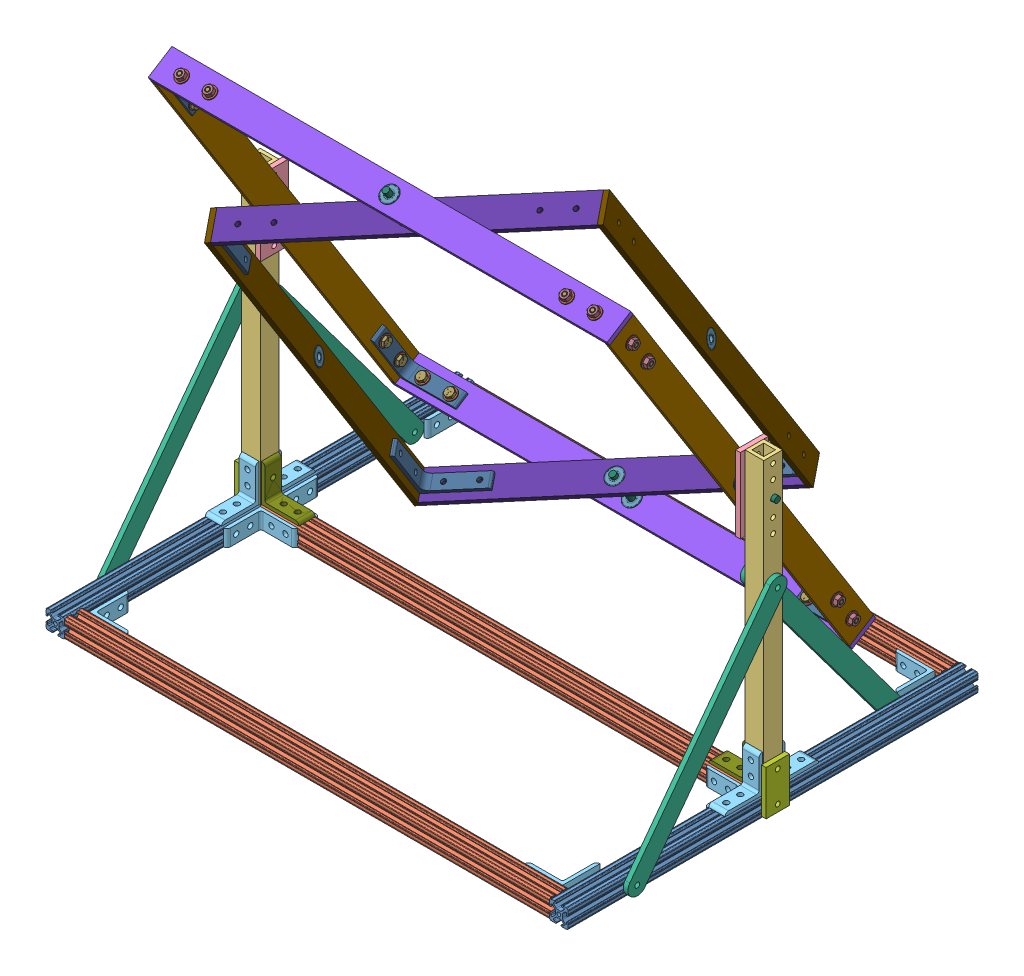
SolidWorks assembly Tines_Assy, configuration Default. Lengths in mm.
Overall size (720.72 664.68 555.62).
126 component instances, 18 part files, 37 mates.
Components (placement in the parent):
- TinesBase_Rails-1: TinesBase_Rails [47065T568] at (481.4535 301.031 444.4013) size (25.4 25.4 555.62)
- TinesBase_Stretcher-5: TinesBase_Stretcher [47065T568] at (140.141 301.031 179.2888) x (0 0 -1) z (1 0 0) size (25.4 25.4 657.22)
- TinesBase_Stretcher-6: TinesBase_Stretcher [47065T568] at (140.141 301.031 444.4013) x (0 0 -1) z (1 0 0) size (25.4 25.4 657.22)
- TinesBase_Stretcher-7: TinesBase_Stretcher [47065T568] at (140.141 301.031 709.5138) x (0 0 -1) z (1 0 0) size (25.4 25.4 657.22)
- TinesBase_Rails-3: TinesBase_Rails [47065T568] at (-201.1715 301.031 444.4013) size (25.4 25.4 555.62)
- Tines_Post-2: Tines_Post [47065T568] at (481.4535 510.581 444.4013) x (1 0 0) z (0 -1 0) size (25.4 25.4 393.7)
- Tines_Post-3: Tines_Post [47065T568] at (-201.1715 510.581 444.4013) x (1 0 0) z (0 -1 0) size (25.4 25.4 393.7)
- BearingSpacer^Tines_Assy-1: BearingSpacer^Tines_Assy [Default] at (462.4035 656.631 444.4013) x (0 -1 0) z (0 0 1) size (101.6 6.35 38.1) (virtual)
- BearingSpacer^Tines_Assy-2: BearingSpacer^Tines_Assy [Default] at (-188.4715 656.631 444.4013) x (0 -1 0) z (0 0 1) size (101.6 6.35 38.1) (virtual)
- 47065T239_Silver Corner Bracket-1: 47065T239_Silver Corner Bracket [47065T239] at (-180.817 301.031 696.8138) x (1 0 0) z (0 1 0) size (50.8 50.8 22.23)
- 47065T239_Silver Corner Bracket-2: 47065T239_Silver Corner Bracket [47065T239] at (-188.4715 301.031 456.3075) x (1 0 0) z (0 -1 0) size (50.8 50.8 22.23)
- 47065T239_Silver Corner Bracket-5: 47065T239_Silver Corner Bracket [47065T239] at (461.099 301.031 696.8138) x (-1 0 0) z (0 -1 0) size (50.8 50.8 22.23)
- 47065T239_Silver Corner Bracket-6: 47065T239_Silver Corner Bracket [47065T239] at (468.7535 301.031 456.3075) x (-1 0 0) z (0 1 0) size (50.8 50.8 22.23)
- 47065T239_Silver Corner Bracket-9: 47065T239_Silver Corner Bracket [47065T239] at (-180.817 301.031 191.9888) x (1 0 0) z (0 -1 0) size (50.8 50.8 22.23)
- 47065T239_Silver Corner Bracket-10: 47065T239_Silver Corner Bracket [47065T239] at (-188.4715 301.031 432.495) x (1 0 0) z (0 1 0) size (50.8 50.8 22.23)
- 47065T239_Silver Corner Bracket-11: 47065T239_Silver Corner Bracket [47065T239] at (461.099 301.031 191.9888) x (-1 0 0) z (0 1 0) size (50.8 50.8 22.23)
- 47065T239_Silver Corner Bracket-12: 47065T239_Silver Corner Bracket [47065T239] at (468.7535 301.031 432.495) x (-1 0 0) z (0 -1 0) size (50.8 50.8 22.23)
- 47065T239_Silver Corner Bracket-13: 47065T239_Silver Corner Bracket [47065T239] at (-201.1715 313.731 457.1013) x (0 1 0) z (1 0 0) size (50.8 50.8 22.23)
- 47065T239_Silver Corner Bracket-14: 47065T239_Silver Corner Bracket [47065T239] at (481.4535 313.731 457.1013) x (0 1 0) z (1 0 0) size (50.8 50.8 22.23)
- 47065T239_Silver Corner Bracket-15: 47065T239_Silver Corner Bracket [47065T239] at (-201.1715 313.731 431.7013) x (0 1 0) z (-1 0 0) size (50.8 50.8 22.23)
- 47065T239_Silver Corner Bracket-16: 47065T239_Silver Corner Bracket [47065T239] at (481.4535 313.731 431.7013) x (0 1 0) z (-1 0 0) size (50.8 50.8 22.23)
- Big Bar^Tines_Assy-1: Big Bar^Tines_Assy [Default] at (462.4035 428.031 349.1513) x (0 -0.8 -0.6) z (0 -0.6 0.8) size (342.9 6.35 25.4) (virtual)
- Big Bar^Tines_Assy-2: Big Bar^Tines_Assy [Default] at (494.1535 428.031 539.6513) x (0 -0.8 0.6) z (0 0.6 0.8) size (342.9 6.35 25.4) (virtual)
- Big Bar^Tines_Assy-3: Big Bar^Tines_Assy [Default] at (-213.8715 428.031 539.6513) x (0 -0.8 0.6) z (0 -0.6 -0.8) size (342.9 6.35 25.4) (virtual)
- Big Bar^Tines_Assy-4: Big Bar^Tines_Assy [Default] at (-182.1215 428.031 349.1513) x (0 -0.8 -0.6) z (0 0.6 -0.8) size (342.9 6.35 25.4) (virtual)
- TinesPost Facebracket^Tines_Assy-1: TinesPost Facebracket^Tines_Assy [Default] at (494.1535 321.6685 444.4013) x (0 -1 0) z (0 0 1) size (60.32 6.35 31.75) (virtual)
- TinesPost Facebracket^Tines_Assy-2: TinesPost Facebracket^Tines_Assy [Default] at (-213.8715 321.6685 444.4013) x (0 -1 0) z (0 0 -1) size (60.32 6.35 31.75) (virtual)
- OutR_22mm-2: OutR_22mm [Default] at (139.924 656.2272 445.0411) x (0.999995 0.001674 -0.002652) z (-0.003135 0.533741 -0.845642) size (717.82 639.44 40.05)
  - OutR_L_22mm-1: OutR_L_22mm [Default] at (0.2194 -311.15 0.7559) x (0.999995 0 -0.003135) z (0.003135 0 0.999995) size (622.3 6.35 38.1)
  - OutR_L_22mm-2: OutR_L_22mm [Default] at (0.2194 311.15 0.7559) x (-0.999995 0 0.003135) z (0.003135 0 0.999995) size (622.3 6.35 38.1)
  - OutR_S_22mm-1: OutR_S_22mm [Default] at (-304.5791 0 1.7116) x (0 1 0) z (0.003135 0 0.999995) size (609.6 6.35 38.1)
  - OutR_S_22mm-2: OutR_S_22mm [Default] at (305.0179 0 -0.1998) x (0 -1 0) z (0.003135 0 0.999995) size (609.6 6.35 38.1)
  - Stand_Bracket_3in-1: Stand_Bracket_3in [8982K254] at (266.9181 266.7 -0.0803) x (0.999995 0 -0.003135) z (-0.003135 0 -0.999995) size (76.2 76.2 19.05)
  - Stand_Bracket_3in-2: Stand_Bracket_3in [8982K254] at (-266.7 266.9181 -0.0803) x (0 0.999995 -0.003135) z (0 -0.003135 -0.999995) size (76.2 76.2 19.05)
  - Stand_Bracket_3in-3: Stand_Bracket_3in [8982K254] at (-266.9181 -266.7 -0.0803) x (-0.999995 0 -0.003135) z (0.003135 0 -0.999995) size (76.2 76.2 19.05)
  - Stand_Bracket_3in-4: Stand_Bracket_3in [8982K254] at (266.7 -266.9181 -0.0803) x (0 -0.999995 -0.003135) z (0 0.003135 -0.999995) size (76.2 76.2 19.05)
  - 90107A029_316 Stainless Steel Washer-1: 90107A029_316 Stainless Steel Washer [90107A029] at (241.5182 298.9453 -0.0007) size (15.88 1.09 15.88)
  - 92965A540_Black-Oxide Grade 5 Steel Hex Head Screws-1: 92965A540_Black-Oxide Grade 5 Steel Hex Head Screws [92965A540] at (241.5182 306.4859 -0.0007) x (0 1 0) z (-0.999784 0 0.020761) size (23.49 12.83 11.11)
  - 95462A029_Medium-Strength Steel Hex Nut-1: 95462A029_Medium-Strength Steel Hex Nut [95462A029] at (241.5182 315.0203 -0.0007) x (0.295019 0 -0.955491) z (0 1 0) size (11.11 12.83 6.51)
  - 90107A029_316 Stainless Steel Washer-2: 90107A029_316 Stainless Steel Washer [90107A029] at (241.5182 311.15 -0.0007) size (15.88 1.09 15.88)
  - 90107A029_316 Stainless Steel Washer-3: 90107A029_316 Stainless Steel Washer [90107A029] at (279.618 311.15 -0.1201) size (15.88 1.09 15.88)
  - 95462A029_Medium-Strength Steel Hex Nut-2: 95462A029_Medium-Strength Steel Hex Nut [95462A029] at (279.618 315.0203 -0.1201) x (0.295019 0 -0.955491) z (0 1 0) size (11.11 12.83 6.51)
  - 92965A540_Black-Oxide Grade 5 Steel Hex Head Screws-2: 92965A540_Black-Oxide Grade 5 Steel Hex Head Screws [92965A540] at (279.618 306.4859 -0.1201) x (0 1 0) z (-0.999784 0 0.020761) size (23.49 12.83 11.11)
  - 90107A029_316 Stainless Steel Washer-4: 90107A029_316 Stainless Steel Washer [90107A029] at (279.618 298.9453 -0.1201) size (15.88 1.09 15.88)
  - 90107A029_316 Stainless Steel Washer-5: 90107A029_316 Stainless Steel Washer [90107A029] at (299.1632 241.3 -0.1814) x (0.00001 0.999995 0.003135) z (-0.003135 0.003135 -0.99999) size (15.88 1.09 15.88)
  - 92965A540_Black-Oxide Grade 5 Steel Hex Head Screws-3: 92965A540_Black-Oxide Grade 5 Steel Hex Head Screws [92965A540] at (306.7038 241.3 -0.2051) x (0.999995 0 -0.003135) z (-0.000055 0.999845 -0.017626) size (23.49 12.83 11.11)
  - 95462A029_Medium-Strength Steel Hex Nut-3: 95462A029_Medium-Strength Steel Hex Nut [95462A029] at (315.2392 241.3 -0.2318) x (-0.002993 0.298014 -0.954557) z (-0.999995 0 0.003135) size (11.11 12.83 6.51)
  - 90107A029_316 Stainless Steel Washer-6: 90107A029_316 Stainless Steel Washer [90107A029] at (311.3679 241.3 -0.2197) x (0.00001 0.999995 0.003135) z (-0.003135 0.003135 -0.99999) size (15.88 1.09 15.88)
  - 90107A029_316 Stainless Steel Washer-7: 90107A029_316 Stainless Steel Washer [90107A029] at (311.3679 279.4 -0.2197) x (0.00001 0.999995 0.003135) z (-0.003135 0.003135 -0.99999) size (15.88 1.09 15.88)
  - 95462A029_Medium-Strength Steel Hex Nut-4: 95462A029_Medium-Strength Steel Hex Nut [95462A029] at (315.2392 279.4 -0.2318) x (-0.002993 0.298014 -0.954557) z (-0.999995 0 0.003135) size (11.11 12.83 6.51)
  - 92965A540_Black-Oxide Grade 5 Steel Hex Head Screws-4: 92965A540_Black-Oxide Grade 5 Steel Hex Head Screws [92965A540] at (306.7038 279.4 -0.2051) x (0.999995 0 -0.003135) z (-0.000055 0.999845 -0.017626) size (23.49 12.83 11.11)
  - 90107A029_316 Stainless Steel Washer-8: 90107A029_316 Stainless Steel Washer [90107A029] at (299.1632 279.4 -0.1814) x (0.00001 0.999995 0.003135) z (-0.003135 0.003135 -0.99999) size (15.88 1.09 15.88)
  - 90107A029_316 Stainless Steel Washer-9: 90107A029_316 Stainless Steel Washer [90107A029] at (-241.3 299.1632 -0.1814) x (-0.999995 0.00001 0.003135) z (-0.003135 -0.003135 -0.99999) size (15.88 1.09 15.88)
  - 90107A029_316 Stainless Steel Washer-10: 90107A029_316 Stainless Steel Washer [90107A029] at (-299.1632 -241.3 -0.1814) x (-0.00001 -0.999995 0.003135) z (0.003135 -0.003135 -0.99999) size (15.88 1.09 15.88)
  - 90107A029_316 Stainless Steel Washer-11: 90107A029_316 Stainless Steel Washer [90107A029] at (241.3 -299.1632 -0.1814) x (0.999995 -0.00001 0.003135) z (0.003135 0.003135 -0.99999) size (15.88 1.09 15.88)
  - 92965A540_Black-Oxide Grade 5 Steel Hex Head Screws-5: 92965A540_Black-Oxide Grade 5 Steel Hex Head Screws [92965A540] at (-241.3 306.7038 -0.2051) x (0 0.999995 -0.003135) z (-0.999845 -0.000055 -0.017626) size (23.49 12.83 11.11)
  - 92965A540_Black-Oxide Grade 5 Steel Hex Head Screws-6: 92965A540_Black-Oxide Grade 5 Steel Hex Head Screws [92965A540] at (-306.7038 -241.3 -0.2051) x (-0.999995 0 -0.003135) z (0.000055 -0.999845 -0.017626) size (23.49 12.83 11.11)
  - 92965A540_Black-Oxide Grade 5 Steel Hex Head Screws-7: 92965A540_Black-Oxide Grade 5 Steel Hex Head Screws [92965A540] at (241.3 -306.7038 -0.2051) x (0 -0.999995 -0.003135) z (0.999845 0.000055 -0.017626) size (23.49 12.83 11.11)
  - 95462A029_Medium-Strength Steel Hex Nut-5: 95462A029_Medium-Strength Steel Hex Nut [95462A029] at (-241.3 315.2392 -0.2318) x (-0.298014 -0.002993 -0.954557) z (0 -0.999995 0.003135) size (11.11 12.83 6.51)
  - 95462A029_Medium-Strength Steel Hex Nut-6: 95462A029_Medium-Strength Steel Hex Nut [95462A029] at (-315.2392 -241.3 -0.2318) x (0.002993 -0.298014 -0.954557) z (0.999995 0 0.003135) size (11.11 12.83 6.51)
  - 95462A029_Medium-Strength Steel Hex Nut-7: 95462A029_Medium-Strength Steel Hex Nut [95462A029] at (241.3 -315.2392 -0.2318) x (0.298014 0.002993 -0.954557) z (0 0.999995 0.003135) size (11.11 12.83 6.51)
  - 90107A029_316 Stainless Steel Washer-12: 90107A029_316 Stainless Steel Washer [90107A029] at (-241.3 311.3679 -0.2197) x (-0.999995 0.00001 0.003135) z (-0.003135 -0.003135 -0.99999) size (15.88 1.09 15.88)
  - 90107A029_316 Stainless Steel Washer-13: 90107A029_316 Stainless Steel Washer [90107A029] at (-311.3679 -241.3 -0.2197) x (-0.00001 -0.999995 0.003135) z (0.003135 -0.003135 -0.99999) size (15.88 1.09 15.88)
  - 90107A029_316 Stainless Steel Washer-14: 90107A029_316 Stainless Steel Washer [90107A029] at (241.3 -311.3679 -0.2197) x (0.999995 -0.00001 0.003135) z (0.003135 0.003135 -0.99999) size (15.88 1.09 15.88)
  - 90107A029_316 Stainless Steel Washer-15: 90107A029_316 Stainless Steel Washer [90107A029] at (-279.4 311.3679 -0.2197) x (-0.999995 0.00001 0.003135) z (-0.003135 -0.003135 -0.99999) size (15.88 1.09 15.88)
  - 90107A029_316 Stainless Steel Washer-16: 90107A029_316 Stainless Steel Washer [90107A029] at (-311.3679 -279.4 -0.2197) x (-0.00001 -0.999995 0.003135) z (0.003135 -0.003135 -0.99999) size (15.88 1.09 15.88)
  - 90107A029_316 Stainless Steel Washer-17: 90107A029_316 Stainless Steel Washer [90107A029] at (279.4 -311.3679 -0.2197) x (0.999995 -0.00001 0.003135) z (0.003135 0.003135 -0.99999) size (15.88 1.09 15.88)
  - 95462A029_Medium-Strength Steel Hex Nut-8: 95462A029_Medium-Strength Steel Hex Nut [95462A029] at (-279.4 315.2392 -0.2318) x (-0.298014 -0.002993 -0.954557) z (0 -0.999995 0.003135) size (11.11 12.83 6.51)
  - 95462A029_Medium-Strength Steel Hex Nut-9: 95462A029_Medium-Strength Steel Hex Nut [95462A029] at (-315.2392 -279.4 -0.2318) x (0.002993 -0.298014 -0.954557) z (0.999995 0 0.003135) size (11.11 12.83 6.51)
  - 95462A029_Medium-Strength Steel Hex Nut-10: 95462A029_Medium-Strength Steel Hex Nut [95462A029] at (279.4 -315.2392 -0.2318) x (0.298014 0.002993 -0.954557) z (0 0.999995 0.003135) size (11.11 12.83 6.51)
  - 92965A540_Black-Oxide Grade 5 Steel Hex Head Screws-8: 92965A540_Black-Oxide Grade 5 Steel Hex Head Screws [92965A540] at (-279.4 306.7038 -0.2051) x (0 0.999995 -0.003135) z (-0.999845 -0.000055 -0.017626) size (23.49 12.83 11.11)
  - 92965A540_Black-Oxide Grade 5 Steel Hex Head Screws-9: 92965A540_Black-Oxide Grade 5 Steel Hex Head Screws [92965A540] at (-306.7038 -279.4 -0.2051) x (-0.999995 0 -0.003135) z (0.000055 -0.999845 -0.017626) size (23.49 12.83 11.11)
  - 92965A540_Black-Oxide Grade 5 Steel Hex Head Screws-10: 92965A540_Black-Oxide Grade 5 Steel Hex Head Screws [92965A540] at (279.4 -306.7038 -0.2051) x (0 -0.999995 -0.003135) z (0.999845 0.000055 -0.017626) size (23.49 12.83 11.11)
  - 90107A029_316 Stainless Steel Washer-18: 90107A029_316 Stainless Steel Washer [90107A029] at (-279.4 299.1632 -0.1814) x (-0.999995 0.00001 0.003135) z (-0.003135 -0.003135 -0.99999) size (15.88 1.09 15.88)
  - 90107A029_316 Stainless Steel Washer-19: 90107A029_316 Stainless Steel Washer [90107A029] at (-299.1632 -279.4 -0.1814) x (-0.00001 -0.999995 0.003135) z (0.003135 -0.003135 -0.99999) size (15.88 1.09 15.88)
  - 90107A029_316 Stainless Steel Washer-20: 90107A029_316 Stainless Steel Washer [90107A029] at (279.4 -299.1632 -0.1814) x (0.999995 -0.00001 0.003135) z (0.003135 0.003135 -0.99999) size (15.88 1.09 15.88)
  - 90107A029_316 Stainless Steel Washer-21: 90107A029_316 Stainless Steel Washer [90107A029] at (-311.15 241.5182 -0.0007) x (0 1 0) z (0 0 1) size (15.88 1.09 15.88)
  - 90107A029_316 Stainless Steel Washer-22: 90107A029_316 Stainless Steel Washer [90107A029] at (-241.5182 -311.15 -0.0007) x (-1 0 0) z (0 0 1) size (15.88 1.09 15.88)
  - 90107A029_316 Stainless Steel Washer-23: 90107A029_316 Stainless Steel Washer [90107A029] at (311.15 -241.5182 -0.0007) x (0 -1 0) z (0 0 1) size (15.88 1.09 15.88)
  - 95462A029_Medium-Strength Steel Hex Nut-11: 95462A029_Medium-Strength Steel Hex Nut [95462A029] at (-315.0203 241.5182 -0.0007) x (0 0.295019 -0.955491) z (-1 0 0) size (11.11 12.83 6.51)
  - 95462A029_Medium-Strength Steel Hex Nut-12: 95462A029_Medium-Strength Steel Hex Nut [95462A029] at (-241.5182 -315.0203 -0.0007) x (-0.295019 0 -0.955491) z (0 -1 0) size (11.11 12.83 6.51)
  - 95462A029_Medium-Strength Steel Hex Nut-13: 95462A029_Medium-Strength Steel Hex Nut [95462A029] at (315.0203 -241.5182 -0.0007) x (0 -0.295019 -0.955491) z (1 0 0) size (11.11 12.83 6.51)
  - 92965A540_Black-Oxide Grade 5 Steel Hex Head Screws-11: 92965A540_Black-Oxide Grade 5 Steel Hex Head Screws [92965A540] at (-306.4859 241.5182 -0.0007) x (-1 0 0) z (0 -0.999784 0.020761) size (23.49 12.83 11.11)
  - 92965A540_Black-Oxide Grade 5 Steel Hex Head Screws-12: 92965A540_Black-Oxide Grade 5 Steel Hex Head Screws [92965A540] at (-241.5182 -306.4859 -0.0007) x (0 -1 0) z (0.999784 0 0.020761) size (23.49 12.83 11.11)
  - 92965A540_Black-Oxide Grade 5 Steel Hex Head Screws-13: 92965A540_Black-Oxide Grade 5 Steel Hex Head Screws [92965A540] at (306.4859 -241.5182 -0.0007) x (1 0 0) z (0 0.999784 0.020761) size (23.49 12.83 11.11)
  - 90107A029_316 Stainless Steel Washer-24: 90107A029_316 Stainless Steel Washer [90107A029] at (-298.9453 241.5182 -0.0007) x (0 1 0) z (0 0 1) size (15.88 1.09 15.88)
  - 90107A029_316 Stainless Steel Washer-25: 90107A029_316 Stainless Steel Washer [90107A029] at (-241.5182 -298.9453 -0.0007) x (-1 0 0) z (0 0 1) size (15.88 1.09 15.88)
  - 90107A029_316 Stainless Steel Washer-26: 90107A029_316 Stainless Steel Washer [90107A029] at (298.9453 -241.5182 -0.0007) x (0 -1 0) z (0 0 1) size (15.88 1.09 15.88)
  - 90107A029_316 Stainless Steel Washer-27: 90107A029_316 Stainless Steel Washer [90107A029] at (-311.15 279.618 -0.1201) x (0 1 0) z (0 0 1) size (15.88 1.09 15.88)
  - 90107A029_316 Stainless Steel Washer-28: 90107A029_316 Stainless Steel Washer [90107A029] at (-279.618 -311.15 -0.1201) x (-1 0 0) z (0 0 1) size (15.88 1.09 15.88)
  - 90107A029_316 Stainless Steel Washer-29: 90107A029_316 Stainless Steel Washer [90107A029] at (311.15 -279.618 -0.1201) x (0 -1 0) z (0 0 1) size (15.88 1.09 15.88)
  - 95462A029_Medium-Strength Steel Hex Nut-14: 95462A029_Medium-Strength Steel Hex Nut [95462A029] at (-315.0203 279.618 -0.1201) x (0 0.295019 -0.955491) z (-1 0 0) size (11.11 12.83 6.51)
  - 95462A029_Medium-Strength Steel Hex Nut-15: 95462A029_Medium-Strength Steel Hex Nut [95462A029] at (-279.618 -315.0203 -0.1201) x (-0.295019 0 -0.955491) z (0 -1 0) size (11.11 12.83 6.51)
  - 95462A029_Medium-Strength Steel Hex Nut-16: 95462A029_Medium-Strength Steel Hex Nut [95462A029] at (315.0203 -279.618 -0.1201) x (0 -0.295019 -0.955491) z (1 0 0) size (11.11 12.83 6.51)
  - 92965A540_Black-Oxide Grade 5 Steel Hex Head Screws-14: 92965A540_Black-Oxide Grade 5 Steel Hex Head Screws [92965A540] at (-306.4859 279.618 -0.1201) x (-1 0 0) z (0 -0.999784 0.020761) size (23.49 12.83 11.11)
  - 92965A540_Black-Oxide Grade 5 Steel Hex Head Screws-15: 92965A540_Black-Oxide Grade 5 Steel Hex Head Screws [92965A540] at (-279.618 -306.4859 -0.1201) x (0 -1 0) z (0.999784 0 0.020761) size (23.49 12.83 11.11)
  - 92965A540_Black-Oxide Grade 5 Steel Hex Head Screws-16: 92965A540_Black-Oxide Grade 5 Steel Hex Head Screws [92965A540] at (306.4859 -279.618 -0.1201) x (1 0 0) z (0 0.999784 0.020761) size (23.49 12.83 11.11)
  - 90107A029_316 Stainless Steel Washer-30: 90107A029_316 Stainless Steel Washer [90107A029] at (-298.9453 279.618 -0.1201) x (0 1 0) z (0 0 1) size (15.88 1.09 15.88)
  - 90107A029_316 Stainless Steel Washer-31: 90107A029_316 Stainless Steel Washer [90107A029] at (-279.618 -298.9453 -0.1201) x (-1 0 0) z (0 0 1) size (15.88 1.09 15.88)
  - 90107A029_316 Stainless Steel Washer-32: 90107A029_316 Stainless Steel Washer [90107A029] at (298.9453 -279.618 -0.1201) x (0 -1 0) z (0 0 1) size (15.88 1.09 15.88)
  - 4668K133_Permanently Lubricated Stainless Steel Ball Bearing-1: 4668K133_Permanently Lubricated Stainless Steel Ball Bearing [4668K133] at (0.2194 -308.3 0.7559) x (1 0 0) z (0 1 0) size (22 22 7)
  - 4668K133_Permanently Lubricated Stainless Steel Ball Bearing-2: 4668K133_Permanently Lubricated Stainless Steel Ball Bearing [4668K133] at (308.3 0.2194 0.7559) x (0 1 0) z (-1 0 0) size (22 22 7)
  - 4668K133_Permanently Lubricated Stainless Steel Ball Bearing-3: 4668K133_Permanently Lubricated Stainless Steel Ball Bearing [4668K133] at (-0.2194 308.3 0.7559) x (-1 0 0) z (0 -1 0) size (22 22 7)
  - 4668K133_Permanently Lubricated Stainless Steel Ball Bearing-4: 4668K133_Permanently Lubricated Stainless Steel Ball Bearing [4668K133] at (-308.3 -0.2194 0.7559) x (0 -1 0) z (1 0 0) size (22 22 7)
  - StandShaft-6: StandShaft [Default] at (359.1182 0.2194 0.7559) x (0 -0.204961 -0.97877) z (0 0.97877 -0.204961) size (8 63.5 8)
  - StandShaft-7: StandShaft [Default] at (-358.6724 0.2194 3.0065) x (-0.006138 -0.204961 -0.978751) z (0.001285 -0.97877 0.204957) size (8 63.5 8)
  - StandShaft-8: StandShaft [Default] at (-0.2194 319.7177 0.7559) x (-0.032217 0 0.999481) z (0.999481 0 0.032217) size (8 63.5 8)
  - StandShaft-9: StandShaft [Default] at (-0.2194 -319.7177 0.7559) x (-0.032217 0 0.999481) z (-0.999481 0 -0.032217) size (8 63.5 8)
- PostBracket-1: PostBracket [47065T239] at (-188.4715 313.731 444.4013) x (0 1 0) z (0 0 -1) size (50.8 50.8 22.23)
- PostBracket-2: PostBracket [47065T239] at (468.7535 313.731 444.4013) x (0 1 0) z (0 0 1) size (50.8 50.8 22.23)
- PostBracket-3: PostBracket [47065T239] at (-188.4715 313.731 444.4013) x (0 1 0) z (0 0 -1) size (50.8 50.8 22.23)
- InR_22mm-1: InR_22mm [Default] at (104.6324 642.9479 453.2917) x (0.863347 0.269333 -0.426723) z (-0.504611 0.460806 -0.730086) size (419.1 534.7 38.1)
  - InR_S_22mm-1: InR_S_22mm [Default] at (38.1353 259.8741 -5.122) x (-1 0 0) z (0 0 1) size (406.4 6.35 38.1)
  - InR_L_22mm-1: InR_L_22mm [Default] at (241.3353 -6.8259 -5.122) x (0 1 0) z (0 0 -1) size (533.4 6.35 38.1)
  - InR_S_22mm-2: InR_S_22mm [Default] at (38.1353 -273.5259 -5.122) x (-1 0 0) z (0 0 -1) size (406.4 6.35 38.1)
  - InR_L_22mm-2: InR_L_22mm [Default] at (-165.0647 -6.8259 -5.122) x (0 -1 0) z (0 0 -1) size (533.4 6.35 38.1)
  - Stand_Bracket_3in-1: Stand_Bracket_3in [8982K254] at (-126.9647 215.4241 -5.122) x (0 1 0) z (0 0 -1) size (76.2 76.2 19.05)
  - Stand_Bracket_3in-2: Stand_Bracket_3in [8982K254] at (-126.9647 -229.0759 -5.122) x (-1 0 0) z (0 0 -1) size (76.2 76.2 19.05)
  - Stand_Bracket_3in-3: Stand_Bracket_3in [8982K254] at (203.2353 -229.0759 -5.122) size (76.2 76.2 19.05)
  - Stand_Bracket_3in-4: Stand_Bracket_3in [8982K254] at (203.2353 215.4241 -5.122) x (0 1 0) z (0 0 1) size (76.2 76.2 19.05)
  - 4668K133_Permanently Lubricated Stainless Steel Ball Bearing-1: 4668K133_Permanently Lubricated Stainless Steel Ball Bearing [4668K133] at (38.1353 -270.6759 -5.122) x (1 0 0) z (0 -1 0) size (22 22 7)
  - 4668K133_Permanently Lubricated Stainless Steel Ball Bearing-2: 4668K133_Permanently Lubricated Stainless Steel Ball Bearing [4668K133] at (38.1353 257.0241 -5.122) x (-1 0 0) z (0 1 0) size (22 22 7)
  - 4668K133_Permanently Lubricated Stainless Steel Ball Bearing-3: 4668K133_Permanently Lubricated Stainless Steel Ball Bearing [4668K133] at (-167.9147 -6.8259 -5.122) x (0 1 0) z (1 0 0) size (22 22 7)
  - 4668K133_Permanently Lubricated Stainless Steel Ball Bearing-4: 4668K133_Permanently Lubricated Stainless Steel Ball Bearing [4668K133] at (244.1853 -6.8259 -5.122) x (0 -1 0) z (-1 0 0) size (22 22 7)
- 4668K133_Permanently Lubricated Stainless Steel Ball Bearing-1: 4668K133_Permanently Lubricated Stainless Steel Ball Bearing [4668K133] at (-184.9715 656.631 444.4013) x (0 -0.191778 0.981438) z (1 0 0) size (22 22 7)
- 4668K133_Permanently Lubricated Stainless Steel Ball Bearing-2: 4668K133_Permanently Lubricated Stainless Steel Ball Bearing [4668K133] at (465.2535 656.631 444.4013) x (0 0.191778 -0.981438) z (-1 0 0) size (22 22 7)
Mates (geometry in assembly coordinates):
- Coincident1: coincident anti-aligned: plane of TinesBase_Rails-1 through (468.7535 305.2214 722.2138) normal (-1 0 0); plane of TinesBase_Stretcher-5 through (468.7535 289.2702 175.0984) normal (1 0 0)
- Coincident2: coincident aligned: plane of TinesBase_Rails-1 through (477.2631 313.731 722.2138) normal (0 1 0); plane of TinesBase_Stretcher-5 through (468.7535 313.731 175.0984) normal (0 1 0)
- Coincident3: coincident aligned: plane of TinesBase_Rails-1 through (485.6439 289.2702 166.5888) normal (0 0 -1); plane of TinesBase_Stretcher-5 through (468.7535 305.2214 166.5888) normal (0 0 -1)
- Coincident7: coincident anti-aligned: plane of TinesBase_Rails-1 through (477.2631 313.731 722.2138) normal (0 1 0); plane of Tines_Post-2 through (481.4535 313.731 444.4013) normal (0 -1 0)
- Coincident8: coincident aligned: plane of TinesBase_Rails-1 through (494.1535 305.2214 722.2138) normal (1 0 0); plane of Tines_Post-2 through (494.1535 313.731 431.7013) normal (1 0 0)
- Coincident9: coincident aligned: plane of TinesBase_Stretcher-6 through (468.7535 305.2214 457.1013) normal (0 0 1); plane of Tines_Post-2 through (468.7535 313.731 457.1013) normal (0 0 1)
- Coincident13: coincident anti-aligned: plane of Tines_Post-2 through (468.7535 313.731 431.7013) normal (-1 0 0); plane of BearingSpacer^Tines_Assy-1 through (468.7535 656.631 444.4013) normal (1 0 0)
- Coincident14: coincident aligned: plane of Tines_Post-2 through (481.4535 707.431 444.4013) normal (0 1 0); plane of BearingSpacer^Tines_Assy-1 through (468.7535 707.431 425.3513) normal (0 1 0)
- Coincident15: coincident: point of Tines_Post-2; unknown of BearingSpacer^Tines_Assy-1
- Coincident17: coincident anti-aligned: plane of TinesBase_Stretcher-7 through (468.7535 305.2214 696.8138) normal (0 0 -1); plane of 47065T239_Silver Corner Bracket-1 through (-130.017 312.1435 696.8138) normal (0 0 1)
- Distance3: distance = 1.5875 mm aligned: plane of 47065T239_Silver Corner Bracket-1 through (-180.817 312.1435 650.789) normal (0 1 0); plane of TinesBase_Rails-3 through (-196.9811 313.731 722.2138) normal (0 1 0)
- Coincident22: coincident anti-aligned: plane of TinesBase_Rails-3 through (-188.4715 305.2214 722.2138) normal (1 0 0); plane of 47065T239_Silver Corner Bracket-2 through (-188.4715 289.9185 456.3075) normal (-1 0 0)
- Distance5: distance = 1.5875 mm aligned: plane of 47065T239_Silver Corner Bracket-2 through (-188.4715 312.1435 502.3323) normal (0 1 0); plane of TinesBase_Rails-3 through (-196.9811 313.731 722.2138) normal (0 1 0)
- Coincident25: coincident anti-aligned: plane of TinesBase_Rails-3 through (-196.9811 313.731 722.2138) normal (0 1 0); plane of 47065T239_Silver Corner Bracket-13 through (-190.059 313.731 457.1013) normal (0 -1 0)
- Coincident26: coincident anti-aligned: plane of Tines_Post-3 through (-213.8715 313.731 457.1013) normal (0 0 1); plane of 47065T239_Silver Corner Bracket-13 through (-190.059 364.531 457.1013) normal (0 0 -1)
- Distance6: distance = 1.5875 mm aligned: plane of 47065T239_Silver Corner Bracket-13 through (-212.284 313.731 503.1261) normal (-1 0 0); plane of TinesBase_Rails-3 through (-213.8715 305.2214 722.2138) normal (-1 0 0)
- Concentric2: concentric anti-aligned: cylinder of Tines_Post-2 through (468.7535 555.031 444.4013) axis (-1 0 0) radius 3.2639; cylinder of Big Bar^Tines_Assy-1 through (468.7535 555.031 444.4013) axis (1 0 0) radius 3.3735
- Coincident28: coincident anti-aligned: plane of Tines_Post-2 through (468.7535 313.731 431.7013) normal (-1 0 0); plane of Big Bar^Tines_Assy-1 through (468.7535 428.031 349.1513) normal (1 0 0)
- Concentric3: concentric anti-aligned: cylinder of Tines_Post-2 through (468.7535 555.031 444.4013) axis (-1 0 0) radius 3.2639; cylinder of Big Bar^Tines_Assy-2 through (500.5035 555.031 444.4013) axis (1 0 0) radius 3.3735
- Coincident29: coincident anti-aligned: plane of Tines_Post-2 through (494.1535 313.731 431.7013) normal (1 0 0); plane of Big Bar^Tines_Assy-2 through (494.1535 428.031 539.6513) normal (-1 0 0)
- Concentric4: concentric anti-aligned: cylinder of Tines_Post-2 through (468.7535 342.306 444.4013) axis (-1 0 0) radius 3.2639; cylinder of TinesPost Facebracket^Tines_Assy-1 through (500.5035 342.306 444.4013) axis (1 0 0) radius 3.2639
- Coincident30: coincident anti-aligned: plane of Tines_Post-2 through (494.1535 313.731 431.7013) normal (1 0 0); plane of TinesPost Facebracket^Tines_Assy-1 through (494.1535 321.6685 444.4013) normal (-1 0 0)
- Parallel2: parallel aligned: plane of Tines_Post-2 through (468.7535 313.731 457.1013) normal (0 0 1); plane of TinesPost Facebracket^Tines_Assy-1 through (500.5035 351.831 460.2763) normal (0 0 1)
- Concentric6: concentric aligned: cylinder of BearingSpacer^Tines_Assy-2 through (-182.1215 656.631 444.4013) axis (-1 0 0) radius 10.9982; cylinder of OutR_22mm-2/OutR_S_22mm-1 through (-163.389 656.631 444.4013) axis (-1 0 0) radius 11
- Distance8: distance = 11.1125 mm anti-aligned: plane of OutR_22mm-2/OutR_S_22mm-1 through (-171.009 656.631 444.4013) normal (-1 0 0); plane of BearingSpacer^Tines_Assy-2 through (-182.1215 656.631 444.4013) normal (1 0 0)
- Concentric7: concentric anti-aligned: cylinder of TinesBase_Rails-3 through (-188.4715 301.031 253.9013) axis (1 0 0) radius 3.2639; cylinder of Big Bar^Tines_Assy-4 through (-188.4715 301.031 253.9013) axis (-1 0 0) radius 3.3735
- Concentric8: concentric anti-aligned: cylinder of TinesBase_Rails-3 through (-188.4715 301.031 634.9013) axis (1 0 0) radius 3.2639; cylinder of Big Bar^Tines_Assy-3 through (-220.2215 301.031 634.9013) axis (-1 0 0) radius 3.3735
- Coincident31: coincident anti-aligned: plane of Tines_Post-3 through (-188.4715 313.731 431.7013) normal (1 0 0); plane of PostBracket-1 through (-188.4715 364.531 433.2888) normal (-1 0 0)
- Coincident32: coincident anti-aligned: plane of TinesBase_Stretcher-6 through (468.7535 313.731 440.2109) normal (0 1 0); plane of PostBracket-1 through (-188.4715 313.731 433.2888) normal (0 -1 0)
- Concentric9: concentric aligned: cylinder of Tines_Post-3 through (-213.8715 342.306 444.4013) axis (-1 0 0) radius 3.2639; cylinder of PostBracket-1 through (-137.6715 342.306 444.4013) axis (-1 0 0) radius 3.5687
- Coincident33: coincident anti-aligned: plane of TinesBase_Stretcher-6 through (468.7535 313.731 448.5916) normal (0 1 0); plane of PostBracket-2 through (468.7535 313.731 455.5138) normal (0 -1 0)
- Concentric10: concentric anti-aligned: cylinder of Tines_Post-2 through (468.7535 342.306 444.4013) axis (-1 0 0) radius 3.2639; cylinder of PostBracket-2 through (417.9535 342.306 444.4013) axis (1 0 0) radius 3.5687
- Coincident34: coincident anti-aligned: plane of Tines_Post-2 through (468.7535 313.731 431.7013) normal (-1 0 0); plane of PostBracket-2 through (468.7535 364.531 455.5138) normal (1 0 0)
- Concentric13: concentric anti-aligned: cylinder of OutR_22mm-2/OutR_L_22mm-2 through (140.141 398.8781 281.7162) axis (0 -0.845646 -0.533744) radius 11; cylinder of InR_22mm-1/InR_S_22mm-1 through (140.141 430.0232 301.374) axis (0 0.845646 0.533744) radius 11
- Concentric15: concentric anti-aligned: cylinder of BearingSpacer^Tines_Assy-2 through (-182.1215 656.631 444.4013) axis (-1 0 0) radius 10.9982; cylinder of 4668K133_Permanently Lubricated Stainless Steel Ball Bearing-1 through (-181.4715 656.631 444.4013) axis (1 0 0) radius 11
- Coincident36: coincident anti-aligned: plane of Tines_Post-3 through (-188.4715 313.731 431.7013) normal (1 0 0); plane of 4668K133_Permanently Lubricated Stainless Steel Ball Bearing-1 through (-188.4715 667.4268 446.5108) normal (-1 0 0)
- Distance9: distance = 38.1 mm anti-aligned: plane of InR_22mm-1/InR_S_22mm-2 through (140.141 882.1649 586.7507) normal (0 0.845646 0.533744); plane of OutR_22mm-2/OutR_L_22mm-1 through (140.141 914.384 607.0864) normal (0 -0.845646 -0.533744)
